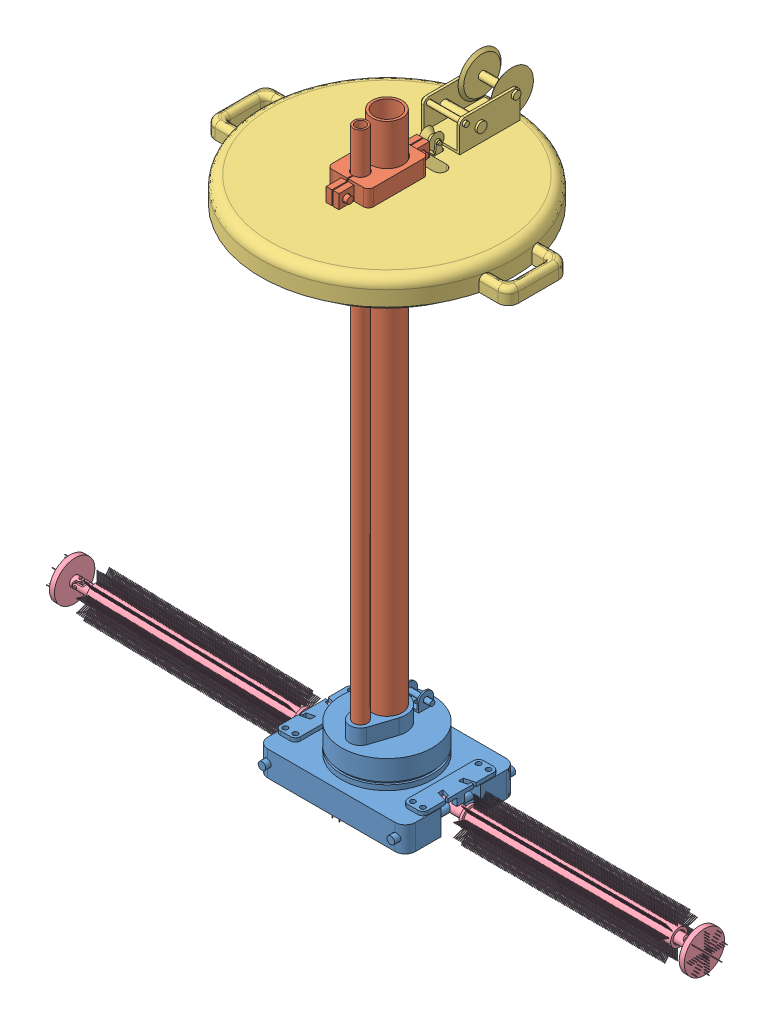
SolidWorks assembly limpia tinacos m2, configuration Predeterminado. Lengths in mm.
Overall size (1277.96 1173.01 507.9).
5 component instances, 4 part files, 15 mates.
Components (placement in the parent):
- base giratoria m2-1: base giratoria m2 [Predeterminado] at (4.7147 -143.9089 292.5037) size (292.5 149 240)
- mastil m2-1: mastil m2 [Predeterminado] at (4.7147 -143.9089 292.5037) size (82 1050 179.2)
- tapa m2-1: tapa m2 [Predeterminado] at (4.7147 743.0911 292.5037) size (600 172.5 507.9)
- soporte de cepillos m2-1: soporte de cepillos m2 [Predeterminado] at (117.2147 -223.8792 292.5037) x (0.999998 -0.001978 0) z (0 0 1) size (526 84 80.19)
- soporte de cepillos m2-2: soporte de cepillos m2 [Predeterminado] at (-107.7898 -224.2752 292.5037) x (-0.999702 0.024418 0) z (0 0 1) size (526 84 80.19)
Mates (geometry in assembly coordinates):
- Concéntrica1: concentric aligned: circle of base giratoria m2-1; circle of mastil m2-1
- Concéntrica2: concentric anti-aligned: circle of mastil m2-1; circle of tapa m2-1
- Concéntrica3: concentric anti-aligned: circle of base giratoria m2-1; circle of mastil m2-1
- Coincidente2: coincident anti-aligned: plane of base giratoria m2-1 through (4.7147 -143.9089 292.5037) normal (0 1 0); plane of mastil m2-1 through (4.7147 -143.9089 292.5037) normal (0 -1 0)
- Concéntrica4: concentric anti-aligned: circle of mastil m2-1; circle of tapa m2-1
- Coincidente3: coincident anti-aligned: plane of mastil m2-1 through (4.7147 786.0911 345.0037) normal (0 -1 0); plane of tapa m2-1 through (35.7147 786.0911 261.0037) normal (0 1 0)
- Paralelo1: parallel anti-aligned: cylinder of base giratoria m2-1 through (132.2147 -223.9089 172.5037) axis (0 0 1) radius 7.5; cylinder of soporte de cepillos m2-1 through (611.7138 -224.8571 305.0037) axis (0 0 -1) radius 2
- Concéntrica5: concentric aligned: cylinder of base giratoria m2-1 through (132.2147 -223.9089 172.5037) axis (0 0 1) radius 7.5; cylinder of soporte de cepillos m2-1 through (132.2147 -223.9089 282.5037) axis (0 0 1) radius 7.5
- Ancho1: width: plane of base giratoria m2-1 through (110.9665 -248.9089 264.0336) normal (0.258819 0 0.965926); plane of base giratoria m2-1 through (110.9665 -248.9089 320.9738) normal (0.258819 0 -0.965926); cylinder of soporte de cepillos m2-1 through (617.2137 -224.868 292.5037) axis (-0.999998 0.001978 0) radius 10
- Perpendicular1: perpendicular: cylinder of base giratoria m2-1 through (132.2147 -223.9089 172.5037) axis (0 0 1) radius 7.5; cylinder of soporte de cepillos m2-1 through (617.2137 -224.868 292.5037) axis (-0.999998 0.001978 0) radius 10
- Paralelo2: parallel aligned: plane of base giratoria m2-1 through (4.7147 -143.9089 412.5037) normal (0 0 1); plane of soporte de cepillos m2-1 through (611.7138 -224.8571 305.0037) normal (0 0 1)
- Concéntrica6: concentric aligned: cylinder of base giratoria m2-1 through (-122.7853 -223.9089 172.5037) axis (0 0 1) radius 7.5; cylinder of soporte de cepillos m2-2 through (-122.7853 -223.9089 282.5037) axis (0 0 1) radius 7.5
- Tangente3: tangent aligned: cylinder of base giratoria m2-1 through (-122.7853 -223.9089 172.5037) axis (0 0 1) radius 7.5; cylinder of soporte de cepillos m2-2 through (-122.7853 -223.9089 282.5037) axis (0 0 1) radius 7.5
- Perpendicular2: perpendicular: cylinder of base giratoria m2-1 through (-122.7853 -223.9089 172.5037) axis (0 0 1) radius 7.5; cylinder of soporte de cepillos m2-2 through (-607.6407 -212.0664 292.5037) axis (0.999702 -0.024418 0) radius 10
- Ancho2: width: plane of base giratoria m2-1 through (-101.5372 -248.9089 264.0336) normal (-0.258819 0 0.965926); plane of base giratoria m2-1 through (-101.5372 -248.9089 320.9738) normal (-0.258819 0 -0.965926); cylinder of soporte de cepillos m2-2 through (-607.6407 -212.0664 292.5037) axis (0.999702 -0.024418 0) radius 10
